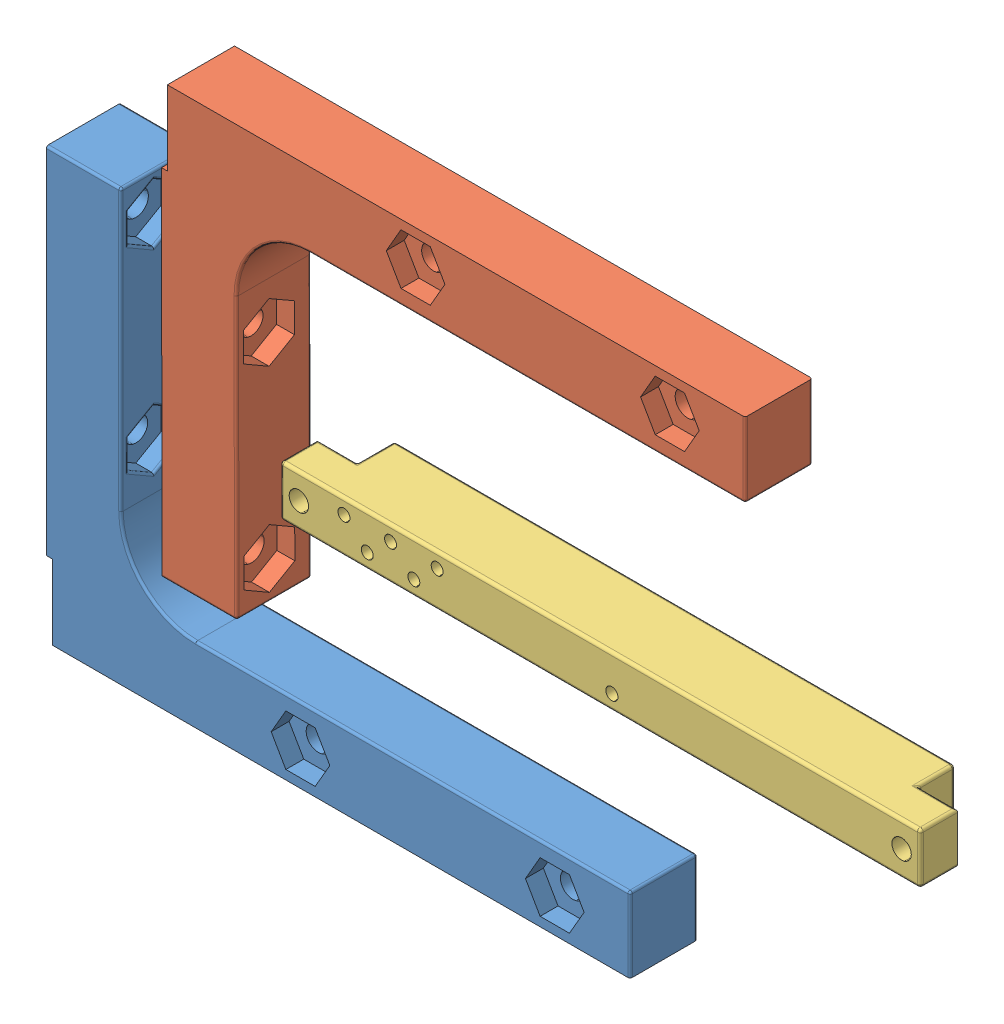
SolidWorks assembly brackets, configuration Default. Lengths in mm.
Overall size (148.65 92.48 12.73).
3 component instances, 3 part files, 1 mates.
Components (placement in the parent):
- leftBrace-1: leftBrace [Default] at origin size (99.29 73.03 12.73)
- RightBrace-1: RightBrace [Default] at (19.5371 130.4205 12.7) x (0.999999 0.001604 0) z (0 0 -1) size (99.29 73.03 12.73)
- DummySlot22Pin-1: DummySlot22Pin [Default] at (94.2083 61.2576 12.7) x (0 -1 0) z (0 0 -1) size (8.64 108.89 12.7)
Mates (geometry in assembly coordinates):
- Coincident10: coincident aligned: plane of DummySlot22Pin-1 through (94.2083 61.2576 12.7) normal (0 0 1); plane of leftBrace-1 through (25.4 44.45 12.7) normal (0 0 1)
